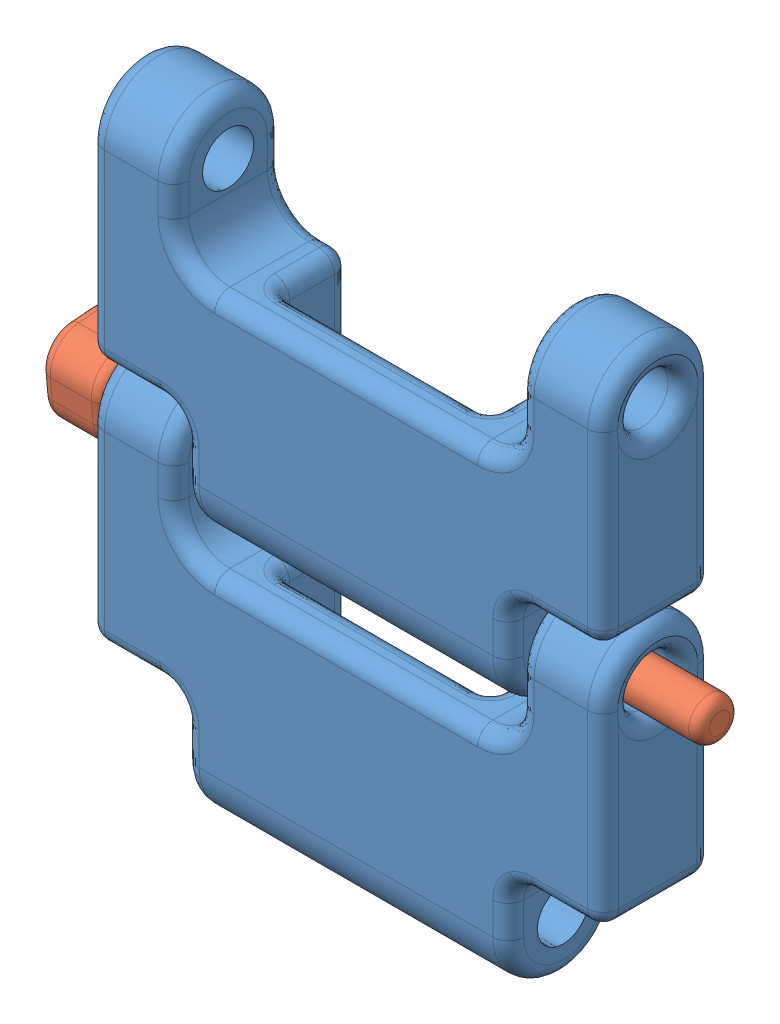
SolidWorks assembly Montagem Dentes Esteira, configuration Valor predeterminado. Lengths in mm.
Overall size (31 29.02 5.58).
3 component instances, 2 part files, 6 mates.
Components (placement in the parent):
- Dente Esteira - Engrenagem-1: Dente Esteira - Engrenagem [Valor predeterminado] at origin size (25 17.17 5.58)
- Dente Esteira - Engrenagem-2: Dente Esteira - Engrenagem [Valor predeterminado] at (0 11.85 0) size (25 17.17 5.58)
- Eixo Junção Esteira-1: Eixo Junção Esteira [Valor predeterminado] at (1.5014 11.85 0) x (0 0.084331 -0.996438) z (-1 0 0) size (4 4 31)
Mates (geometry in assembly coordinates):
- Concêntrico3: concentric anti-aligned: cylinder of Dente Esteira - Engrenagem-2 through (8.39 11.85 0) axis (-1 0 0) radius 1.25; cylinder of Eixo Junção Esteira-1 through (-12.4986 11.85 0) axis (1 0 0) radius 1
- Paralelo1: parallel aligned: cylinder of Dente Esteira - Engrenagem-1 through (-12.5 11.85 0) axis (1 0 0) radius 1.25; cylinder of Eixo Junção Esteira-1 through (-12.4986 11.85 0) axis (1 0 0) radius 1
- Coincidente2: coincident anti-aligned: circle of Dente Esteira - Engrenagem-1; plane of Eixo Junção Esteira-1 through (-12.4986 11.3939 -0.5404) normal (1 0 0)
- Coincidente3: coincident aligned: plane of Dente Esteira - Engrenagem-1 through (5.127 8.39 -2.66) normal (0 0 -1); plane of Dente Esteira - Engrenagem-2 through (5.127 20.24 -2.66) normal (0 0 -1)
- Coincidente4: coincident aligned: plane of Dente Esteira - Engrenagem-1 through (-12.5 0 0) normal (-1 0 0); plane of Dente Esteira - Engrenagem-2 through (-12.5 11.85 0) normal (-1 0 0)
- Concêntrico5: concentric anti-aligned: cylinder of Dente Esteira - Engrenagem-1 through (12.5 11.85 0) axis (-1 0 0) radius 1.25; cylinder of Eixo Junção Esteira-1 through (-12.4986 11.85 0) axis (1 0 0) radius 1
